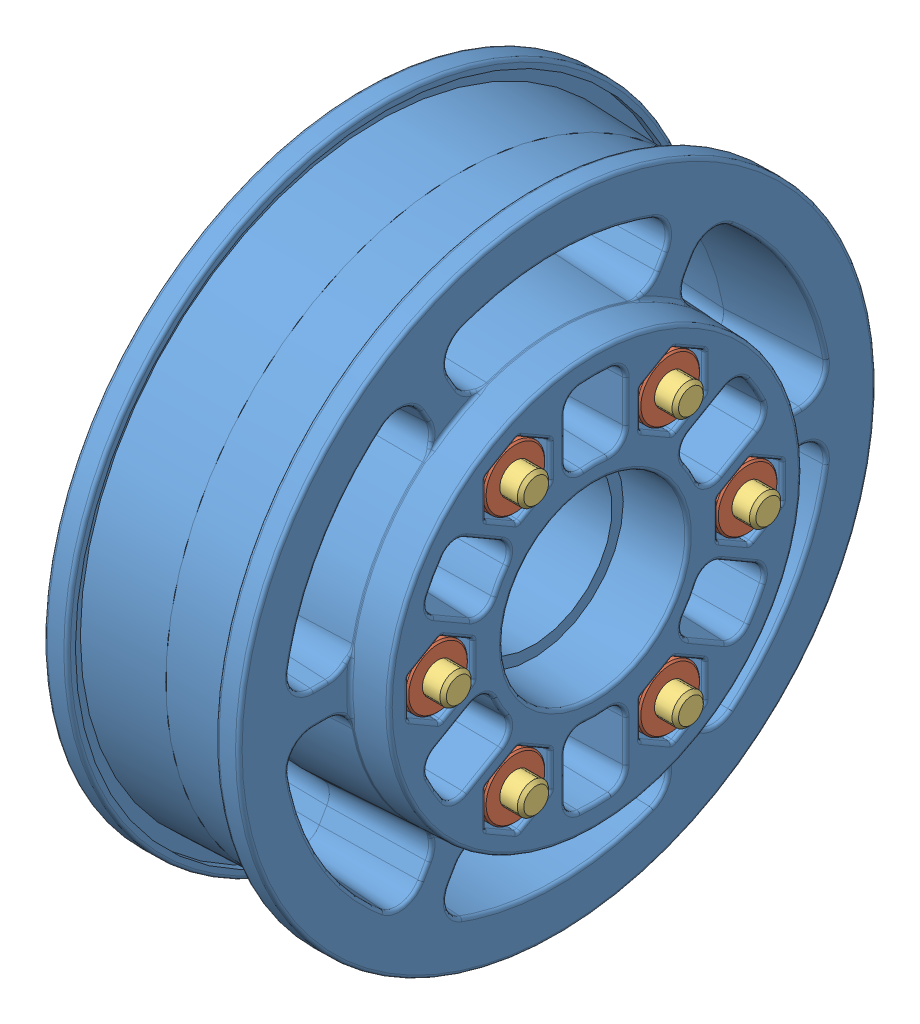
SolidWorks assembly 4in Plaction Wheel, configuration Default. Lengths in mm.
Overall size (44.45 98.05 98.05).
14 component instances, 3 part files, 0 mates.
Components (placement in the parent):
- 4MW_d01-1: 4MW_d01 [Default] at origin size (22.87 98.05 98.05)
- 4MW_d01-2: 4MW_d01 [Default] at (41.656 0 0) x (-1 0 0) z (0 0 -1) size (22.87 98.05 98.05)
- 10-32_nylock_nut-1: 10-32_nylock_nut [Default] at (130.8703 5.9047 -125.8472) x (0 -0.212137 0.97724) z (-1 0 0) size (11.98 11.69 7.5)
- 10-32_nylock_nut-2: 10-32_nylock_nut [Default] at (130.8703 106.0345 68.0372) x (0 -0.740246 -0.672336) z (-1 0 0) size (11.98 11.69 7.5)
- 10-32_nylock_nut-3: 10-32_nylock_nut [Default] at (130.8703 -5.9047 125.8472) x (0 0.212137 -0.97724) z (-1 0 0) size (11.98 11.69 7.5)
- 10-32_nylock_nut-4: 10-32_nylock_nut [Default] at (130.8703 -111.9392 57.81) x (0 0.952383 -0.304904) z (-1 0 0) size (11.98 11.69 7.5)
- 10-32_nylock_nut-5: 10-32_nylock_nut [Default] at (130.8703 -106.0345 -68.0372) x (0 0.740246 0.672336) z (-1 0 0) size (11.98 11.69 7.5)
- 10-32_nylock_nut-6: 10-32_nylock_nut [Default] at (130.8703 111.9392 -57.81) x (0 -0.952383 0.304904) z (-1 0 0) size (11.98 11.69 7.5)
- 10-32x1500_shcs-1: 10-32x1500_shcs [Default] at (58.0517 58.1538 -90.8088) x (0 -0.164314 0.986408) z (1 0 0) size (7.94 7.94 42.93)
- 10-32x1500_shcs-2: 10-32x1500_shcs [Default] at (58.0517 49.5658 95.7671) x (0 -0.772098 -0.635504) z (1 0 0) size (7.94 7.94 42.93)
- 10-32x1500_shcs-3: 10-32x1500_shcs [Default] at (58.0517 -58.1538 90.8088) x (0 0.164314 -0.986408) z (1 0 0) size (7.94 7.94 42.93)
- 10-32x1500_shcs-4: 10-32x1500_shcs [Default] at (58.0517 -107.7197 -4.9583) x (0 0.936411 -0.350904) z (1 0 0) size (7.94 7.94 42.93)
- 10-32x1500_shcs-5: 10-32x1500_shcs [Default] at (58.0517 -49.5658 -95.7671) x (0 0.772098 0.635504) z (1 0 0) size (7.94 7.94 42.93)
- 10-32x1500_shcs-6: 10-32x1500_shcs [Default] at (58.0517 107.7197 4.9583) x (0 -0.936411 0.350904) z (1 0 0) size (7.94 7.94 42.93)
